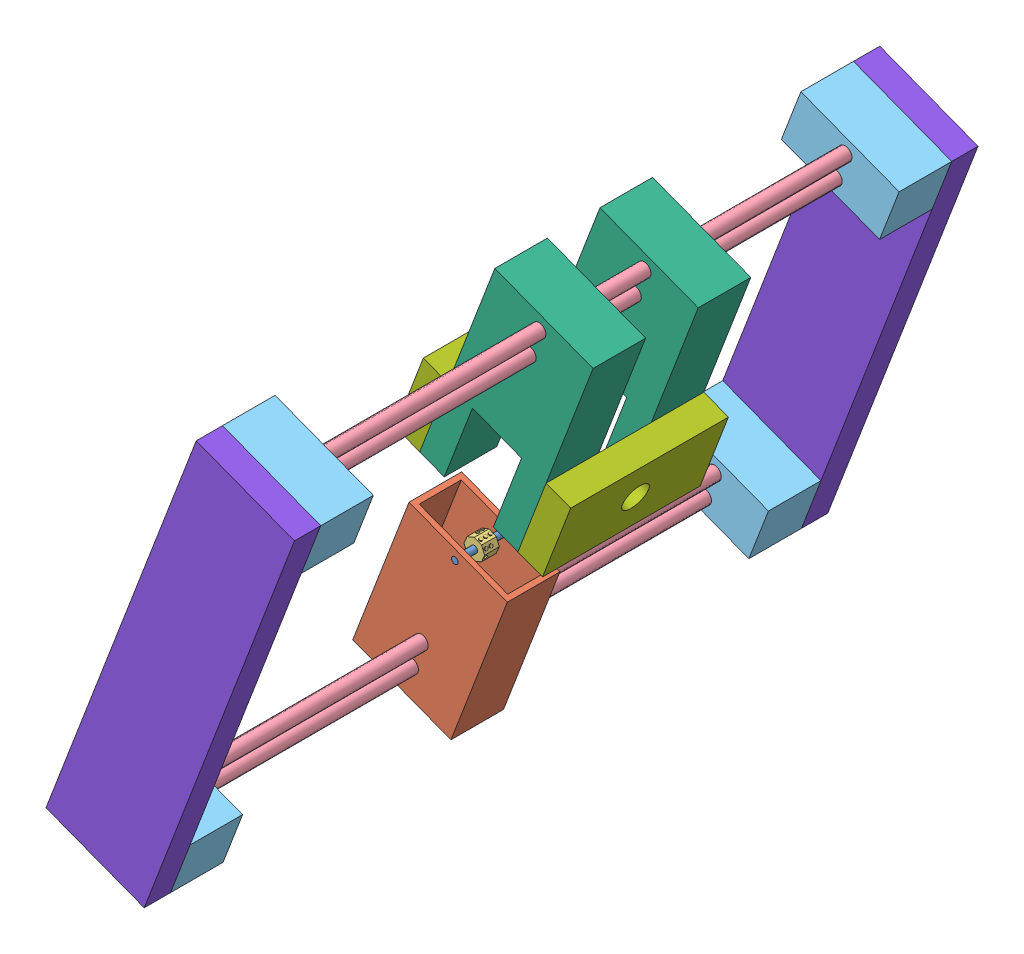
SolidWorks assembly Final Assembly 2.0, configuration Default. Lengths in mm.
Overall size (134.25 218.65 330.2).
19 component instances, 8 part files, 10 mates.
Components (placement in the parent):
- Presser Assambly-1: Presser Assambly [Default] at (84.9365 183.1261 232.8278) size (74.67 89.32 304.8)
  - Roller Axle 2.0-1: Roller Axle 2.0 [Default] at (13.3551 18.2656 14.0484) size (3.17 3.17 25.4)
  - Roller Holder 2.0-1: Roller Holder 2.0 [Default] at (-35.9532 -39.5653 14.0484) x (0.934037 -0.357176 0) z (0 0 1) size (50.8 76.2 25.4)
  - Braile Roller 2.0 -1: Braile Roller 2.0  [Default] at (13.3551 18.2656 22.9378) x (0.999979 -0.006471 0) z (0 0 1) size (9.96 9.96 7.1)
  - Leadscrew 2.0-1: Leadscrew 2.0 [Default] at (-7.5111 -36.3008 -127.52) size (6.6 6.6 304.8)
  - Leadscrew 2.0-2: Leadscrew 2.0 [Default] at (-2.7935 -23.9641 -127.52) size (6.6 6.6 304.8)
  - Pillow Block 2.0-1: Pillow Block 2.0 [Default] at (-33.5944 -33.397 151.88) x (0.934037 -0.357176 0) z (0 0 1) size (50.8 26.42 25.4)
  - Pillow Block 2.0-2: Pillow Block 2.0 [Default] at (-33.5944 -33.397 -127.52) x (0.934037 -0.357176 0) z (0 0 1) size (50.8 26.42 25.4)
- Wheel assembly 2.0-1: Wheel assembly 2.0 [Default] at (84.1108 293.2101 70.2933) x (0.934037 -0.357176 0) z (0 0 1) size (76.2 101.6 304.8)
  - Pillow Block 2.0-1: Pillow Block 2.0 [Default] at (20.6407 31.0632 35.0144) size (50.8 26.42 25.4)
  - Pillow Block 2.0-2: Pillow Block 2.0 [Default] at (20.6407 31.0632 314.4144) size (50.8 26.42 25.4)
  - Wheel Holder 2.0-1: Wheel Holder 2.0 [Default] at (20.6407 -44.1208 182.8676) size (50.8 101.6 25.4)
  - Wheel Holder 2.0-2: Wheel Holder 2.0 [Default] at (20.6407 -44.1208 132.0676) size (50.8 101.6 25.4)
  - Leadscrew 2.0-2: Leadscrew 2.0 [Default] at (46.0407 37.6672 35.0144) size (6.6 6.6 304.8)
  - Leadscrew 2.0-3: Leadscrew 2.0 [Default] at (46.0407 50.8752 35.0144) size (6.6 6.6 304.8)
  - Shoulder Bearing 2.0-1: Shoulder Bearing 2.0 [Default] at (84.1407 -44.1208 132.0676) x (0 0 1) z (-1 0 0) size (76.2 38.1 12.7)
  - Shoulder Bearing 2.0-2: Shoulder Bearing 2.0 [Default] at (7.9407 -44.1208 208.2676) x (0 0 -1) z (1 0 0) size (76.2 38.1 12.7)
- Main Holder-1: Main Holder [Default] at (51.342 149.7292 410.1078) x (0.934037 -0.357176 0) z (0 0 1) size (50.8 203.2 12.7)
- Main Holder-3: Main Holder [Default] at (51.342 149.7292 92.6078) x (0.934037 -0.357176 0) z (0 0 1) size (50.8 203.2 12.7)
Mates (geometry in assembly coordinates):
- Coincident4: coincident anti-aligned: plane of Presser Assambly-1/Pillow Block 2.0-1 through (51.342 149.7292 410.1078) normal (0 0 1); plane of Main Holder-1 through (51.342 149.7292 410.1078) normal (0 0 -1)
- Parallel1: parallel anti-aligned: plane of Presser Assambly-1/Pillow Block 2.0-1 through (60.7772 174.4027 410.1078) normal (0.357176 0.934037 0); plane of Main Holder-1 through (51.342 149.7292 422.8078) normal (-0.357176 -0.934037 0)
- Coincident8: coincident aligned: line of Presser Assambly-1/Pillow Block 2.0-1 through (51.342 149.7292 410.1078) axis (0.934037 -0.357176 0); line of Main Holder-1 through (51.342 149.7292 410.1078) axis (0.934037 -0.357176 0)
- Coincident9: coincident anti-aligned: plane of Presser Assambly-1/Pillow Block 2.0-2 through (51.342 149.7292 105.3078) normal (0 0 -1); plane of Main Holder-3 through (51.342 149.7292 105.3078) normal (0 0 1)
- Coincident10: coincident aligned: line of Presser Assambly-1/Pillow Block 2.0-2 through (51.342 149.7292 105.3078) axis (0.934037 -0.357176 0); line of Main Holder-3 through (51.342 149.7292 105.3078) axis (0.934037 -0.357176 0)
- Coincident11: coincident aligned: line of Presser Assambly-1/Pillow Block 2.0-2 through (98.7911 131.5846 105.3078) axis (0.357176 0.934037 0); line of Main Holder-3 through (98.7911 131.5846 105.3078) axis (0.357176 0.934037 0)
- Coincident12: coincident anti-aligned: plane of Wheel assembly 2.0-1/Pillow Block 2.0-2 through (114.485 314.852 410.1078) normal (0 0 1); plane of Main Holder-1 through (51.342 149.7292 410.1078) normal (0 0 -1)
- Coincident13: coincident aligned: plane of Wheel assembly 2.0-1/Pillow Block 2.0-2 through (123.9202 339.5255 410.1078) normal (0.357176 0.934037 0); plane of Main Holder-1 through (123.9202 339.5255 422.8078) normal (0.357176 0.934037 0)
- Coincident14: coincident aligned: line of Wheel assembly 2.0-1/Pillow Block 2.0-2 through (123.9202 339.5255 410.1078) axis (-0.357176 -0.934037 0); line of Main Holder-1 through (123.9202 339.5255 410.1078) axis (-0.357176 -0.934037 0)
- Coincident15: coincident aligned: line of Wheel assembly 2.0-1/Pillow Block 2.0-1 through (123.9202 339.5255 105.3078) axis (-0.357176 -0.934037 0); line of Main Holder-3 through (123.9202 339.5255 105.3078) axis (-0.357176 -0.934037 0)
